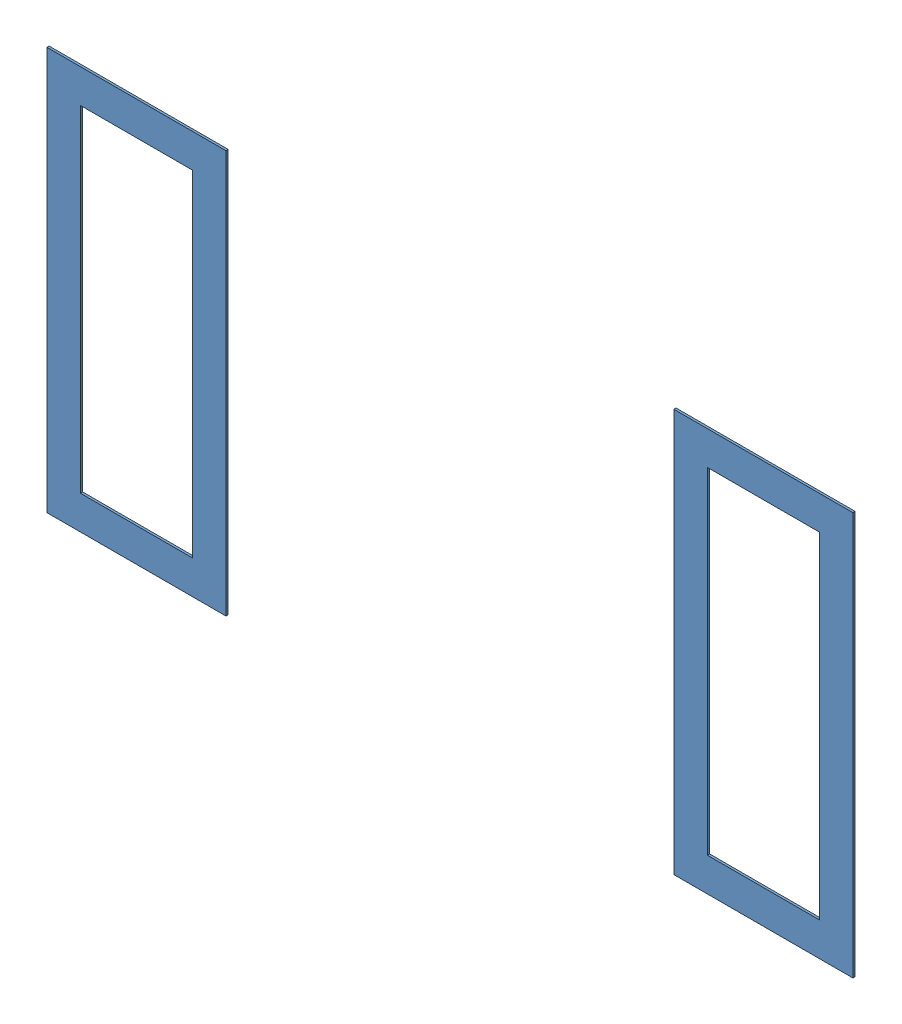
SolidWorks assembly Assem1, configuration Default. Lengths in mm.
Overall size (72 36 0.2).
2 component instances, 1 part files, 3 mates.
Components (placement in the parent):
- ThinRectangle-1: ThinRectangle [Default] at (-43.7517 2.804 21.0822) size (16 36 0.2)
- ThinRectangle-2: ThinRectangle [Default] at (12.2483 2.804 21.0822) size (16 36 0.2)
Mates (geometry in assembly coordinates):
- Coincident1: coincident aligned: line of ThinRectangle-1 through (-35.7517 20.804 21.2822) axis (-1 0 0); line of ThinRectangle-2 through (20.2483 20.804 21.2822) axis (-1 0 0)
- Coincident2: coincident aligned: plane of ThinRectangle-1 through (-43.7517 2.804 21.0822) normal (0 0 -1); plane of ThinRectangle-2 through (12.2483 2.804 21.0822) normal (0 0 -1)
- Distance1: distance = 40 mm: line of ThinRectangle-1 through (-35.7517 -15.196 21.2822) axis (0 1 0); line of ThinRectangle-2 through (4.2483 20.804 21.2822) axis (0 -1 0)
